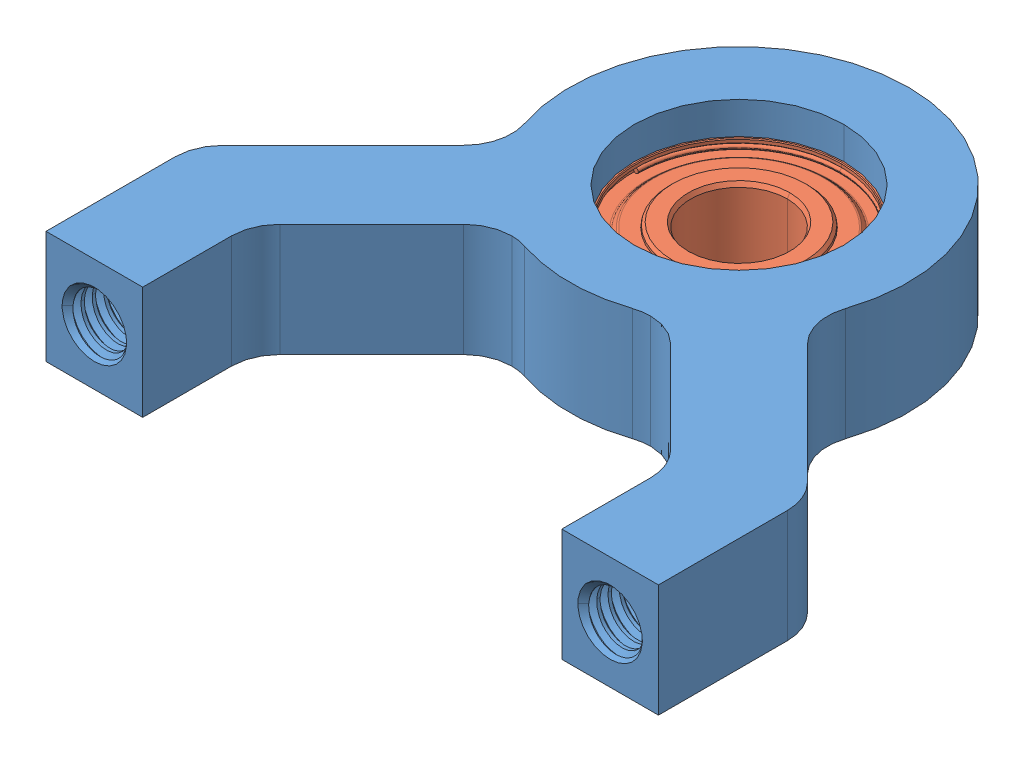
SolidWorks assembly 1602-0032-0006 assembly, configuration Default. Lengths in mm.
Overall size (38 7 34.5).
3 component instances, 2 part files, 0 mates.
Components (placement in the parent):
- 1602-0032-0006 assembly.STEP-1: 1602-0032-0006 assembly.STEP [Default] at origin size (38 7 34.5)
  - 1602-0032-0006.STEP-1: 1602-0032-0006.STEP [Default] at (-34.7118 0.6077 8.7762) size (38 7 34.5)
  - 1600-0515-0006.STEP-1: 1600-0515-0006.STEP [Default] at (-34.7118 0.6077 8.7762) size (15 5 15)
